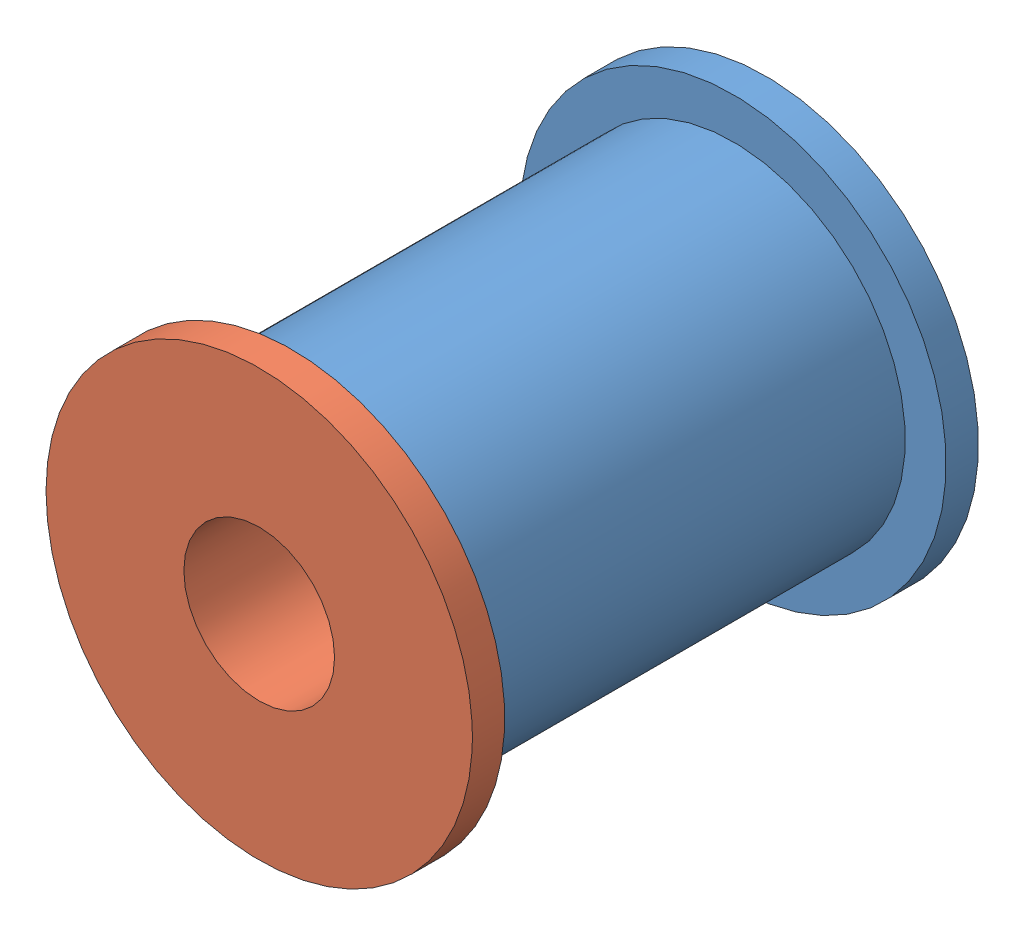
SolidWorks assembly JSummoWheelAsm, configuration Default. Lengths in mm.
Overall size (19.8 19.8 23.5).
2 component instances, 2 part files, 0 mates.
Components (placement in the parent):
- JSumoTireWheel-1: JSumoTireWheel [Default] at (13.758 17.3841 6.9638) size (19.8 19.8 22)
- OutSideCollar-1: OutSideCollar [Default] at origin size (19.8 19.8 6)
